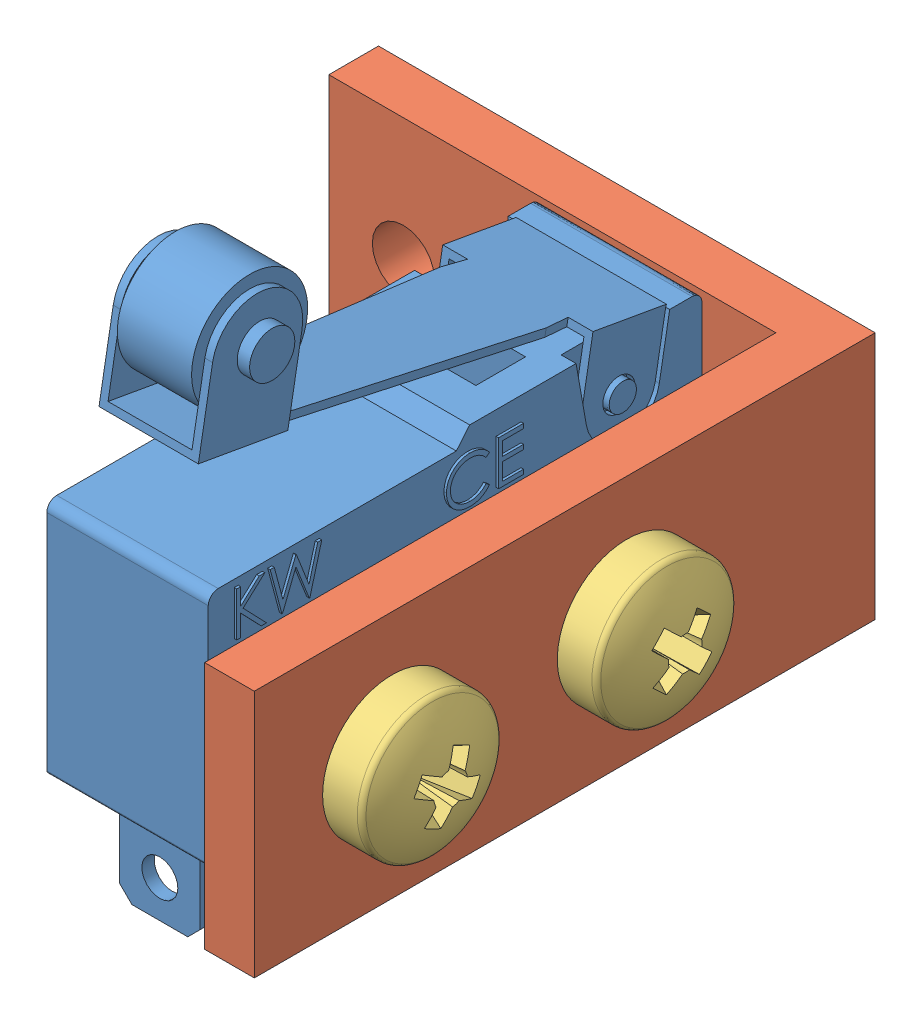
SolidWorks assembly EndSensorModule, configuration End Sensor Module. Lengths in mm.
Overall size (22.35 22.49 25).
4 component instances, 3 part files, 11 mates.
Components (placement in the parent):
- Limit Switch-1: Limit Switch [Default] at (50.1242 56.8994 -5.2001) x (0 -0.000062 1) z (-1 0 0) size (19.88 22.49 6.9)
- SensorMount-1: SensorMount [Default] at (52.3242 49.1484 -9.9754) x (-1 0 0) z (0 1 0) size (20 25 10)
- pan head cross recess screw_din-1: pan head cross recess screw_din [DIN EN ISO 7045 - M3 x 10 - Z - 10N] at (54.7242 49.1484 9.4746) x (-1 0 0) z (0 0.445535 0.895265) size (12.35 5.6 5.6)
- pan head cross recess screw_din-2: pan head cross recess screw_din [DIN EN ISO 7045 - M3 x 10 - Z - 10N] at (54.7242 49.1484 0.0246) x (-1 0 0) z (0 0.679498 0.733678) size (12.35 5.6 5.6)
Mates (geometry in assembly coordinates):
- Concentric1: concentric anti-aligned: cylinder of Limit Switch^EndSensoeModule_cnc_milling_carriage_v1-1 through (53.6242 49.1484 0.0246) axis (-1 0 0) radius 1.225; cylinder of SensorMount-1 through (52.3242 49.1484 0.0246) axis (1 0 0) radius 1.55
- Concentric4: concentric aligned: cylinder of SensorMount-1 through (42.3242 49.1484 -9.9754) axis (0 0 -1) radius 1.25; cylinder of countersunk flat head cross recess screw_iso-2 through (42.3242 49.1484 -22.3254) axis (0 0 -1) radius 1.5
- Concentric5: concentric aligned: cylinder of SensorMount-1 through (35.3242 49.1484 -9.9754) axis (0 0 -1) radius 1.25; cylinder of countersunk flat head cross recess screw_iso-1 through (35.3242 49.1484 -22.3254) axis (0 0 -1) radius 1.5
- Distance3: distance = 6 mm aligned: plane of SensorMount-1 through (32.3242 54.1484 -9.9754) normal (0 0 -1); plane of countersunk flat head cross recess screw_iso-1 through (35.3242 49.1484 -15.9754) normal (0 0 -1)
- Distance4: distance = 6 mm aligned: plane of countersunk flat head cross recess screw_iso-2 through (42.3242 49.1484 -15.9754) normal (0 0 -1); plane of SensorMount-1 through (32.3242 54.1484 -9.9754) normal (0 0 -1)
- Coincident5: coincident anti-aligned: plane of Limit Switch^EndSensoeModule_cnc_milling_carriage_v1-1 through (50.3242 49.1491 -0.1056) normal (1 0 0); plane of SensorMount-1 through (50.3242 54.1484 15.0246) normal (-1 0 0)
- Coincident6: coincident anti-aligned: plane of SensorMount-1 through (52.3242 54.1484 -9.9754) normal (1 0 0); plane of pan head cross recess screw_din-1 through (52.3242 47.8056 10.1429) normal (-1 0 0)
- Concentric6: concentric aligned: cylinder of SensorMount-1 through (52.3242 49.1484 9.4746) axis (1 0 0) radius 1.55; cylinder of pan head cross recess screw_din-1 through (80.1242 49.1484 9.4746) axis (1 0 0) radius 1.5
- Concentric7: concentric aligned: cylinder of SensorMount-1 through (52.3242 49.1484 0.0246) axis (1 0 0) radius 1.55; cylinder of pan head cross recess screw_din-2 through (80.1242 49.1484 0.0246) axis (1 0 0) radius 1.5
- Coincident7: coincident anti-aligned: plane of SensorMount-1 through (52.3242 54.1484 -9.9754) normal (1 0 0); plane of pan head cross recess screw_din-2 through (52.3242 48.0479 1.0438) normal (-1 0 0)
- Concentric8: concentric anti-aligned: cylinder of Limit Switch-1 through (53.6242 49.1484 9.4746) axis (-1 0 0) radius 1.225; cylinder of pan head cross recess screw_din-1 through (80.1242 49.1484 9.4746) axis (1 0 0) radius 1.5
